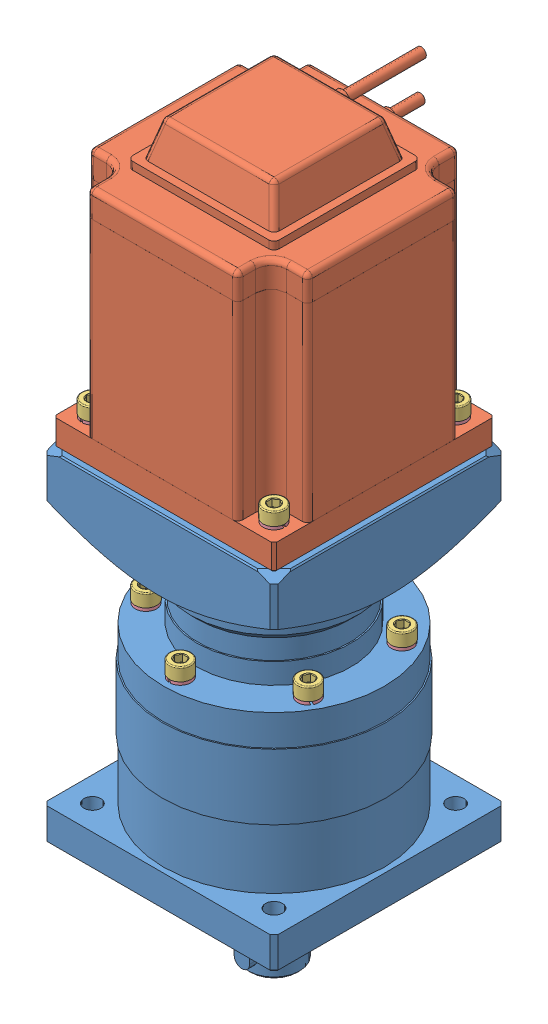
SolidWorks assembly Мотор-редуктор PL86BLF04-PGB15, configuration По умолчанию. Lengths in mm.
Overall size (90 284 102.97).
22 component instances, 4 part files, 15 mates.
Components (placement in the parent):
- Редуктор PGB i_15-1: Редуктор PGB i_15 [По умолчанию] at (-18.6172 -53.2565 0) size (90 173 90)
- Привод BLDC PL86BLF04-1: Привод BLDC PL86BLF04 [По умолчанию] at (-18.6172 79.7435 0) size (85.85 151 100.9)
- Винт М5-6е x 16.109.40Х.019 ГОСТ 11738-84-1: Винт М5-6е x 16.109.40Х.019 ГОСТ 11738-84 [По умолчанию] at (-53.9725 130.9435 35.3553) x (0 -1 0) z (-1 0 0) size (21.15 8.5 8.5)
- Шайба 5 65Г 019 ГОСТ 6402-70-1: Шайба 5 65Г 019 ГОСТ 6402-70 [По умолчанию] at (-53.9725 129.7435 35.3553) x (-1 0 0) z (0 1 0) size (8.3 8.3 1.2)
- Шайба 5 65Г 019 ГОСТ 6402-70-2: Шайба 5 65Г 019 ГОСТ 6402-70 [По умолчанию] at (-53.9725 129.7435 -35.3553) x (0 0 -1) z (0 1 0) size (8.3 8.3 1.2)
- Шайба 5 65Г 019 ГОСТ 6402-70-3: Шайба 5 65Г 019 ГОСТ 6402-70 [По умолчанию] at (16.7382 129.7435 -35.3553) x (1 0 0) z (0 1 0) size (8.3 8.3 1.2)
- Шайба 5 65Г 019 ГОСТ 6402-70-4: Шайба 5 65Г 019 ГОСТ 6402-70 [По умолчанию] at (16.7382 129.7435 35.3553) x (0 0 1) z (0 1 0) size (8.3 8.3 1.2)
- Винт М5-6е x 16.109.40Х.019 ГОСТ 11738-84-2: Винт М5-6е x 16.109.40Х.019 ГОСТ 11738-84 [По умолчанию] at (-53.9725 130.9435 -35.3553) x (0 -1 0) z (0 0 -1) size (21.15 8.5 8.5)
- Винт М5-6е x 16.109.40Х.019 ГОСТ 11738-84-3: Винт М5-6е x 16.109.40Х.019 ГОСТ 11738-84 [По умолчанию] at (16.7382 130.9435 -35.3553) x (0 -1 0) z (1 0 0) size (21.15 8.5 8.5)
- Винт М5-6е x 16.109.40Х.019 ГОСТ 11738-84-4: Винт М5-6е x 16.109.40Х.019 ГОСТ 11738-84 [По умолчанию] at (16.7382 130.9435 35.3553) x (0 -1 0) z (0 0 1) size (21.15 8.5 8.5)
- Шайба 5 65Г 019 ГОСТ 6402-70-5: Шайба 5 65Г 019 ГОСТ 6402-70 [По умолчанию] at (-18.6172 60.2435 36.5) x (-1 0 0) z (0 1 0) size (8.3 8.3 1.2)
- Винт М5-6е x 16.109.40Х.019 ГОСТ 11738-84-5: Винт М5-6е x 16.109.40Х.019 ГОСТ 11738-84 [По умолчанию] at (-18.6172 61.4435 36.5) x (0 -1 0) z (-1 0 0) size (21.15 8.5 8.5)
- Винт М5-6е x 16.109.40Х.019 ГОСТ 11738-84-6: Винт М5-6е x 16.109.40Х.019 ГОСТ 11738-84 [По умолчанию] at (-50.2271 61.4435 18.25) x (0 -1 0) z (-0.5 0 -0.866025) size (21.15 8.5 8.5)
- Винт М5-6е x 16.109.40Х.019 ГОСТ 11738-84-7: Винт М5-6е x 16.109.40Х.019 ГОСТ 11738-84 [По умолчанию] at (-50.2271 61.4435 -18.25) x (0 -1 0) z (0.5 0 -0.866025) size (21.15 8.5 8.5)
- Винт М5-6е x 16.109.40Х.019 ГОСТ 11738-84-8: Винт М5-6е x 16.109.40Х.019 ГОСТ 11738-84 [По умолчанию] at (-18.6172 61.4435 -36.5) x (0 -1 0) z (1 0 0) size (21.15 8.5 8.5)
- Винт М5-6е x 16.109.40Х.019 ГОСТ 11738-84-9: Винт М5-6е x 16.109.40Х.019 ГОСТ 11738-84 [По умолчанию] at (12.9927 61.4435 -18.25) x (0 -1 0) z (0.5 0 0.866025) size (21.15 8.5 8.5)
- Винт М5-6е x 16.109.40Х.019 ГОСТ 11738-84-10: Винт М5-6е x 16.109.40Х.019 ГОСТ 11738-84 [По умолчанию] at (12.9927 61.4435 18.25) x (0 -1 0) z (-0.5 0 0.866025) size (21.15 8.5 8.5)
- Шайба 5 65Г 019 ГОСТ 6402-70-6: Шайба 5 65Г 019 ГОСТ 6402-70 [По умолчанию] at (-50.2271 60.2435 18.25) x (-0.5 0 -0.866025) z (0 1 0) size (8.3 8.3 1.2)
- Шайба 5 65Г 019 ГОСТ 6402-70-7: Шайба 5 65Г 019 ГОСТ 6402-70 [По умолчанию] at (-50.2271 60.2435 -18.25) x (0.5 0 -0.866025) z (0 1 0) size (8.3 8.3 1.2)
- Шайба 5 65Г 019 ГОСТ 6402-70-8: Шайба 5 65Г 019 ГОСТ 6402-70 [По умолчанию] at (-18.6172 60.2435 -36.5) x (1 0 0) z (0 1 0) size (8.3 8.3 1.2)
- Шайба 5 65Г 019 ГОСТ 6402-70-9: Шайба 5 65Г 019 ГОСТ 6402-70 [По умолчанию] at (12.9927 60.2435 -18.25) x (0.5 0 0.866025) z (0 1 0) size (8.3 8.3 1.2)
- Шайба 5 65Г 019 ГОСТ 6402-70-10: Шайба 5 65Г 019 ГОСТ 6402-70 [По умолчанию] at (12.9927 60.2435 18.25) x (-0.5 0 0.866025) z (0 1 0) size (8.3 8.3 1.2)
Mates (geometry in assembly coordinates):
- Концентрический1: concentric anti-aligned: cylinder of Редуктор PGB i_15-1 through (-18.6172 -53.2565 0) axis (0 -1 0) radius 6.35; cylinder of Привод BLDC PL86BLF04-1 through (-18.6172 79.7435 0) axis (0 1 0) radius 10
- Совпадение1: coincident anti-aligned: plane of Редуктор PGB i_15-1 through (-55.1172 119.7435 0) normal (0 1 0); plane of Привод BLDC PL86BLF04-1 through (-78.1172 119.7435 0) normal (0 -1 0)
- Концентрический3: concentric anti-aligned: cylinder of Редуктор PGB i_15-1 through (16.7382 99.7435 -35.3553) axis (0 1 0) radius 2.1; cylinder of Привод BLDC PL86BLF04-1 through (16.7382 134.2435 -35.3553) axis (0 -1 0) radius 3.3
- Концентрический4: concentric anti-aligned: cylinder of Винт М5-6е x 16.109.40Х.019 ГОСТ 11738-84-1 through (-53.9725 114.9435 35.3553) axis (0 1 0) radius 2.5; cylinder of Шайба 5 65Г 019 ГОСТ 6402-70-1 through (-53.9725 130.9435 35.3553) axis (0 -1 0) radius 4.15
- Совпадение2: coincident anti-aligned: plane of Винт М5-6е x 16.109.40Х.019 ГОСТ 11738-84-1 through (-53.9725 130.9435 35.3553) normal (0 -1 0); plane of Шайба 5 65Г 019 ГОСТ 6402-70-1 through (-53.9725 130.9435 35.3553) normal (0 1 0)
- Перпендикулярность1: perpendicular: plane of Винт М5-6е x 16.109.40Х.019 ГОСТ 11738-84-1 through (-52.8178 133.1435 33.3553) normal (0 0 1); plane of Шайба 5 65Г 019 ГОСТ 6402-70-1 through (-54.7447 132.9641 39.5053) normal (-0.939693 -0.34202 0)
- Совпадение3: coincident anti-aligned: plane of Привод BLDC PL86BLF04-1 through (-78.6172 129.7435 0) normal (0 1 0); plane of Шайба 5 65Г 019 ГОСТ 6402-70-1 through (-53.9725 129.7435 35.3553) normal (0 -1 0)
- Концентрический5: concentric anti-aligned: cylinder of Привод BLDC PL86BLF04-1 through (-53.9725 134.2435 35.3553) axis (0 -1 0) radius 3.3; cylinder of Винт М5-6е x 16.109.40Х.019 ГОСТ 11738-84-1 through (-53.9725 114.9435 35.3553) axis (0 1 0) radius 2.5
- Параллельность1: parallel aligned: plane of Привод BLDC PL86BLF04-1 through (24.3078 213.7435 42.925) normal (0 0 1); plane of Винт М5-6е x 16.109.40Х.019 ГОСТ 11738-84-1 through (-52.8178 133.1435 33.3553) normal (0 0 1)
- Совпадение4: coincident anti-aligned: plane of Редуктор PGB i_15-1 through (-48.6172 60.2435 0) normal (0 1 0); plane of Шайба 5 65Г 019 ГОСТ 6402-70-5 through (-18.6172 60.2435 36.5) normal (0 -1 0)
- Концентрический6: concentric anti-aligned: cylinder of Редуктор PGB i_15-1 through (-18.6172 60.2435 36.5) axis (0 1 0) radius 2.1; cylinder of Шайба 5 65Г 019 ГОСТ 6402-70-5 through (-18.6172 61.4435 36.5) axis (0 -1 0) radius 2.55
- Концентрический7: concentric aligned: cylinder of Шайба 5 65Г 019 ГОСТ 6402-70-5 through (-18.6172 61.4435 36.5) axis (0 -1 0) radius 2.55; cylinder of Винт М5-6е x 16.109.40Х.019 ГОСТ 11738-84-5 through (-18.6172 66.4435 36.5) axis (0 -1 0) radius 4.25
- Совпадение5: coincident anti-aligned: plane of Винт М5-6е x 16.109.40Х.019 ГОСТ 11738-84-5 through (-18.6172 61.4435 36.5) normal (0 -1 0); plane of Шайба 5 65Г 019 ГОСТ 6402-70-5 through (-18.6172 61.4435 36.5) normal (0 1 0)
- Параллельность2: parallel aligned: plane of Редуктор PGB i_15-1 through (26.3828 119.7435 45) normal (0 0 1); plane of Винт М5-6е x 16.109.40Х.019 ГОСТ 11738-84-5 through (-17.4625 63.6435 34.5) normal (0 0 1)
- Параллельность3: parallel aligned: plane of Редуктор PGB i_15-1 through (26.3828 119.7435 45) normal (0 0 1); plane of Шайба 5 65Г 019 ГОСТ 6402-70-5
